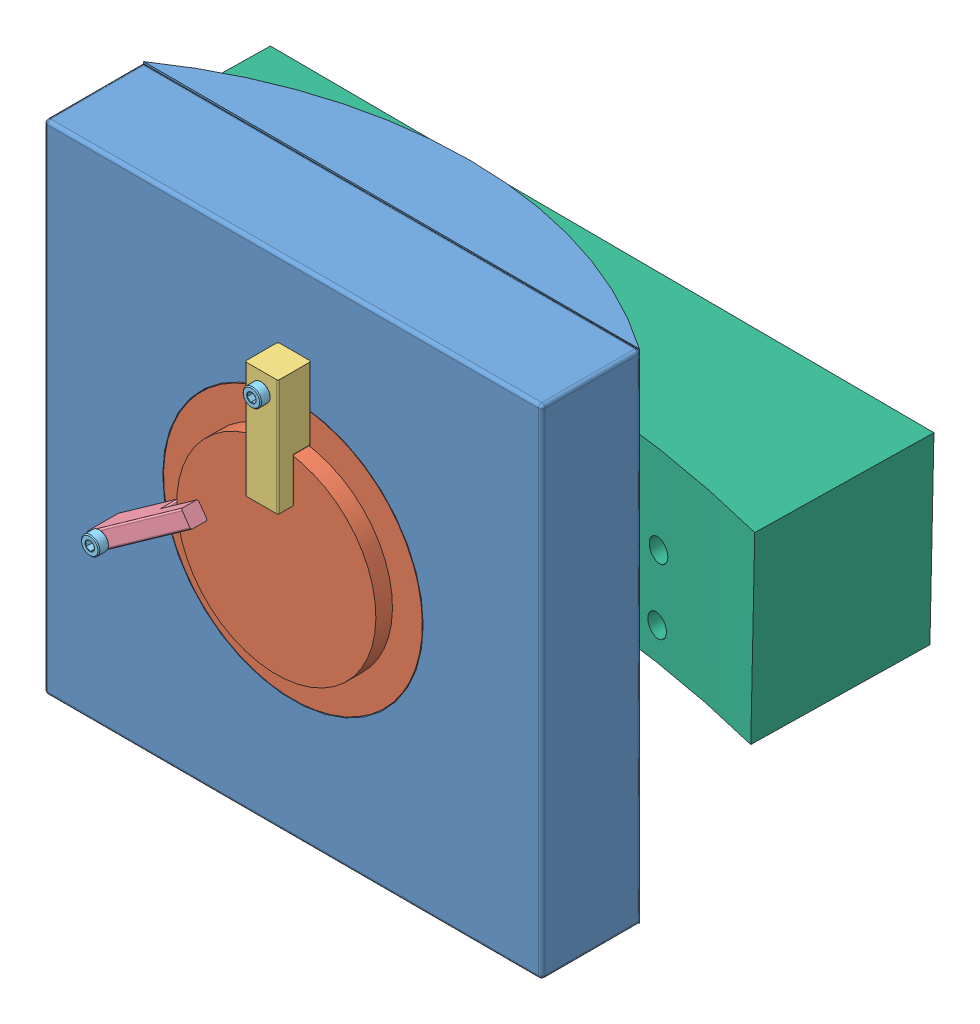
SolidWorks assembly Simulate_Shaker, configuration Default. Lengths in mm.
Overall size (200.27 150 108.96).
7 component instances, 6 part files, 14 mates.
Components (placement in the parent):
- Platform_Shaker-2: Platform_Shaker [Default] at (90.2439 123.5452 183.8601) size (150 150 53.43)
- Outline for Chamber-2: Outline for Chamber [Default] at (90.2439 123.5452 188.8601) x (0.98387 -0.178886 0) z (0.178886 0.98387 0) size (78 15 78)
- Clamp_Shaker_v2-2: Clamp_Shaker_v2 [Default] at (90.7401 158.0452 188.8601) x (0 -1 0) z (0 0 1) size (35 10 10)
- Small_Clamp-1: Small_Clamp [Default] at (53.7624 115.3403 193.8601) x (-0.81553 -0.578715 0) z (0 0 -1) size (35 5 10)
- 91292A026_18-8 Stainless Steel Socket Head Screw-1: 91292A026_18-8 Stainless Steel Socket Head Screw [91292A026] at (90.7401 170.0452 170.3601) x (0.974587 -0.22401 0) z (0 0 1) size (5.5 5.5 53.38)
- 91292A026_18-8 Stainless Steel Socket Head Screw-2: 91292A026_18-8 Stainless Steel Socket Head Screw [91292A026] at (42.0063 106.998 170.3601) x (0.998011 0.063035 0) z (0 0 1) size (5.5 5.5 53.38)
- Servo Mount Shaker-3: Servo Mount Shaker [Default] at (87.4964 128.4353 118.5035) x (0.999989 -0.004705 0) z (0.004705 0.99984 -0.017275) size (200 54.02 57.5)
Mates (geometry in assembly coordinates):
- Coincident14: coincident anti-aligned: plane of Outline for Chamber-2 through (90.2439 123.5452 188.8601) normal (0 0 1); plane of Clamp_Shaker_v2-2 through (90.7401 158.0452 188.8601) normal (0 0 -1)
- Tangent9: tangent anti-aligned: cylinder of Outline for Chamber-2 through (90.2439 123.5452 183.8601) axis (0 0 1) radius 30; plane of Clamp_Shaker_v2-2 through (95.7401 153.5452 183.8601) normal (0 -1 0)
- Parallel3: parallel aligned: plane of Platform_Shaker-2 through (15.2439 198.5452 153.8601) normal (0 1 0); plane of Clamp_Shaker_v2-2 through (85.7401 175.5452 193.8601) normal (0 1 0)
- Parallel4: parallel aligned: plane of Platform_Shaker-2 through (15.2439 198.5452 153.8601) normal (0 1 0); plane of Clamp_Shaker_v2-2 through (85.7401 175.5452 193.8601) normal (0 1 0)
- Parallel6: parallel aligned: plane of Platform_Shaker-2 through (165.2439 48.5452 153.8601) normal (1 0 0); plane of Clamp_Shaker_v2-2 through (95.7401 175.5452 193.8601) normal (1 0 0)
- Parallel7: parallel aligned: plane of Platform_Shaker-2 through (15.2439 48.5452 153.8601) normal (-1 0 0); plane of Clamp_Shaker_v2-2 through (85.7401 175.5452 193.8601) normal (-1 0 0)
- Coincident15: coincident anti-aligned: plane of Platform_Shaker-2 through (90.2439 123.5452 173.8601) normal (0 0 1); plane of Outline for Chamber-2 through (90.2439 123.5452 173.8601) normal (0 0 -1)
- Concentric5: concentric aligned: cylinder of Platform_Shaker-2 through (90.2439 123.5452 173.8601) axis (0 0 1) radius 39.25; cylinder of Outline for Chamber-2 through (90.2439 123.5452 173.8601) axis (0 0 1) radius 39
- Tangent11: tangent anti-aligned: cylinder of Outline for Chamber-2 through (90.2439 123.5452 183.8601) axis (0 0 1) radius 30; plane of Small_Clamp-1 through (55.9855 119.9834 183.8601) normal (0.81553 0.578715 0)
- Coincident18: coincident anti-aligned: plane of Outline for Chamber-2 through (90.2439 123.5452 188.8601) normal (0 0 1); plane of Small_Clamp-1 through (53.7624 115.3403 188.8601) normal (0 0 -1)
- Concentric7: concentric anti-aligned: cylinder of Clamp_Shaker_v2-2 through (90.7401 170.0452 193.8601) axis (0 0 1) radius 1.7; cylinder of 91292A026_18-8 Stainless Steel Socket Head Screw-1 through (90.7401 170.0452 143.8601) axis (0 0 -1) radius 1.5
- Coincident19: coincident anti-aligned: plane of Clamp_Shaker_v2-2 through (90.7401 158.0452 193.8601) normal (0 0 1); plane of 91292A026_18-8 Stainless Steel Socket Head Screw-1 through (88.194 170.6304 193.8601) normal (0 0 -1)
- Concentric8: concentric anti-aligned: cylinder of Small_Clamp-1 through (42.0063 106.998 193.8601) axis (0 0 1) radius 1.7; cylinder of 91292A026_18-8 Stainless Steel Socket Head Screw-2 through (42.0063 106.998 143.8601) axis (0 0 -1) radius 1.5
- Coincident20: coincident anti-aligned: plane of Small_Clamp-1 through (53.7624 115.3403 193.8601) normal (0 0 1); plane of 91292A026_18-8 Stainless Steel Socket Head Screw-2 through (39.399 106.8333 193.8601) normal (0 0 -1)
